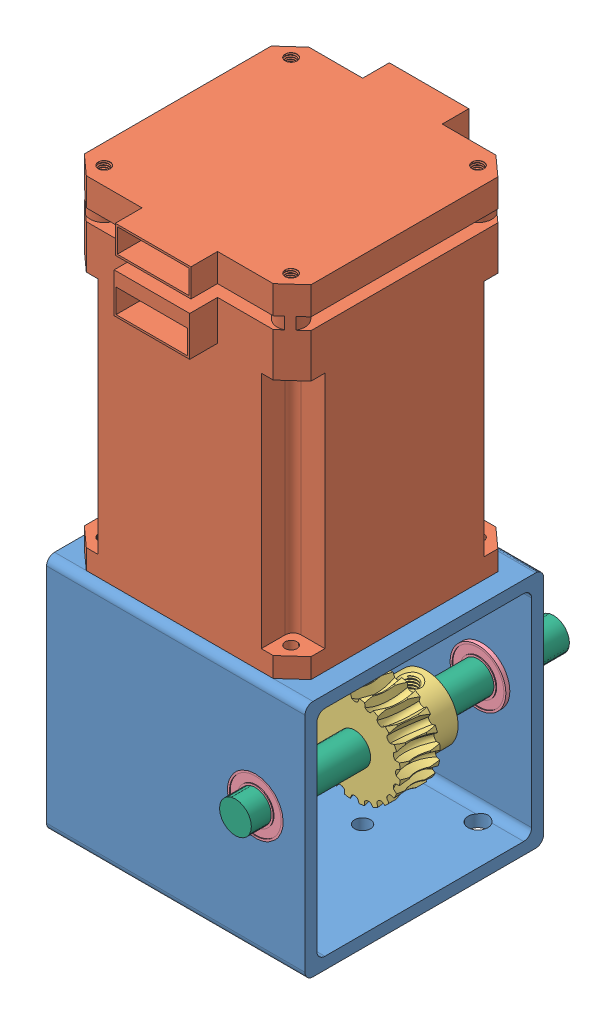
SolidWorks assembly Asm_57Driver_90Degree_Shoulder, configuration 默认. Lengths in mm.
Overall size (65 146 80).
7 component instances, 6 part files, 14 mates.
Components (placement in the parent):
- Part_Flange_57Motor_Shoulder-1: Part_Flange_57Motor_Shoulder [默认] at (26.0668 -4.0802 43.0962) size (65 60 60)
- Part_57Motor-1: Part_57Motor [默认] at (86.0668 141.9198 36.5962) x (-1 0 0) z (0 0 1) size (57 110 69.7)
- Part_Turbine_1Modulus_20Teeth_42SMotor-1: Part_Turbine_1Modulus_20Teeth_42SMotor [默认] at (78.5668 27.9198 18.0962) x (-1 0 0) z (0 -1 0) size (29.84 18 44.58)
- Part_Bearing_MR148ZZ-1: Part_Bearing_MR148ZZ [默认] at (78.5668 27.9198 -12.9038) x (0 0 -1) z (0.425184 0.905107 0) size (4 14 14)
- Part_Bearing_MR148ZZ-2: Part_Bearing_MR148ZZ [默认] at (78.5668 27.9198 43.0962) x (0 0 -1) z (-0.945462 0.325732 0) size (4 14 14)
- Part_Shaft_1Modulus_4Teeth_57SMotor-1: Part_Shaft_1Modulus_4Teeth_57SMotor [默认] at (57.5668 16.4198 13.0962) x (0 1 0) z (-0.930054 0 0.367423) size (36.16 24.18 24.06)
- Part_Axis_8mm_Turbine_Shoulder-1: Part_Axis_8mm_Turbine_Shoulder [默认] at (78.5668 27.9198 -31.9038) size (8 17.7 80)
Mates (geometry in assembly coordinates):
- 重合18: coincident anti-aligned: plane of Part_Flange_57Motor_Shoulder-1 through (91.0668 55.9198 -14.9038) normal (0 1 0); plane of Part_57Motor-1 through (86.0668 55.9198 36.5962) normal (0 -1 0)
- 同心1: concentric aligned: cylinder of Part_Flange_57Motor_Shoulder-1 through (34.0668 -4.0802 -10.4038) axis (0 1 0) radius 2.5; cylinder of Part_57Motor-1 through (34.0668 55.9198 -10.4038) axis (0 1 0) radius 1.5
- 同心2: concentric aligned: cylinder of Part_Flange_57Motor_Shoulder-1 through (34.0668 -4.0802 36.5962) axis (0 1 0) radius 2.5; cylinder of Part_57Motor-1 through (34.0668 55.9198 36.5962) axis (0 1 0) radius 1.5
- 同心3: concentric aligned: cylinder of Part_Flange_57Motor_Shoulder-1 through (78.5668 27.9198 -16.9038) axis (0 0 1) radius 7; cylinder of Part_Bearing_MR148ZZ-1 through (78.5668 27.9198 -16.9038) axis (0 0 1) radius 7
- 重合19: coincident aligned: plane of Part_Flange_57Motor_Shoulder-1 through (91.0668 -2.0802 -16.9038) normal (0 0 -1); plane of Part_Bearing_MR148ZZ-1 through (78.5668 27.9198 -16.9038) normal (0 0 -1)
- 同心4: concentric aligned: cylinder of Part_Flange_57Motor_Shoulder-1 through (78.5668 27.9198 -16.9038) axis (0 0 1) radius 7; cylinder of Part_Bearing_MR148ZZ-2 through (78.5668 27.9198 39.0962) axis (0 0 1) radius 7
- 重合20: coincident aligned: plane of Part_Flange_57Motor_Shoulder-1 through (91.0668 53.9198 43.0962) normal (0 0 1); plane of Part_Bearing_MR148ZZ-2 through (78.5668 27.9198 43.0962) normal (0 0 1)
- 同心5: concentric aligned: cylinder of Part_Turbine_1Modulus_20Teeth_42SMotor-1 through (78.5668 27.9198 8.0962) axis (0 0 1) radius 4; cylinder of Part_Bearing_MR148ZZ-2 through (78.5668 27.9198 39.0962) axis (0 0 1) radius 4
- 同心6: concentric anti-aligned: cylinder of Part_57Motor-1 through (57.5668 31.9198 13.0962) axis (0 1 0) radius 4; cylinder of Part_Shaft_1Modulus_4Teeth_57SMotor-1 through (57.5668 51.4198 13.0962) axis (0 -1 0) radius 4
- 距离1: distance = 3 mm anti-aligned: plane of Part_Shaft_1Modulus_4Teeth_57SMotor-1 through (57.5668 51.4198 13.0962) normal (0 1 0); plane of Part_57Motor-1 through (57.5668 54.4198 13.0962) normal (0 -1 0)
- 平行3: parallel anti-aligned: line of Part_Turbine_1Modulus_20Teeth_42SMotor-1 through (60.5668 46.568 13.0962) axis (0 -1 0); line of Part_Shaft_1Modulus_4Teeth_57SMotor-1 through (57.5668 16.4198 13.0962) axis (0 1 0)
- 距离3: distance = 21 mm: line of Part_Turbine_1Modulus_20Teeth_42SMotor-1 through (78.5668 27.9198 13.0962) axis (0 -1 0); line of Part_Shaft_1Modulus_4Teeth_57SMotor-1 through (57.5668 16.4198 13.0962) axis (0 1 0)
- 同心7: concentric anti-aligned: cylinder of Part_Bearing_MR148ZZ-1 through (78.5668 27.9198 -16.9038) axis (0 0 1) radius 4; cylinder of Part_Axis_8mm_Turbine_Shoulder-1 through (78.5668 27.9198 48.0962) axis (0 0 -1) radius 4
- 距离4: distance = 5 mm aligned: plane of Part_Axis_8mm_Turbine_Shoulder-1 through (78.5668 27.9198 48.0962) normal (0 0 1); plane of Part_Flange_57Motor_Shoulder-1 through (91.0668 53.9198 43.0962) normal (0 0 1)
